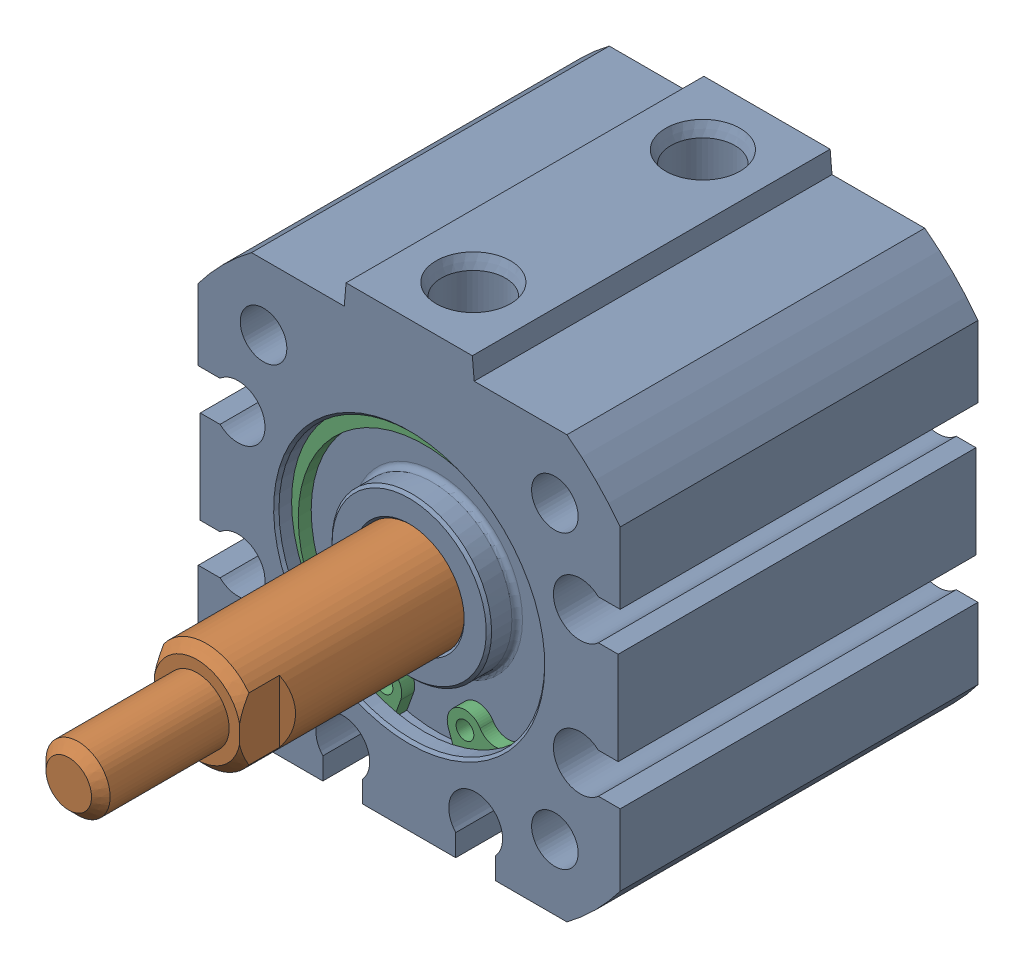
SolidWorks assembly 217-2778-001 Rev2_NCQ8A075-050M_1, configuration Default. Lengths in mm.
Overall size (31.75 33.34 52.54).
3 component instances, 3 part files, 0 mates.
Components (placement in the parent):
- 217-2778-NCQ8A075-050M_NCQ8 Tube_075A_1-1: 217-2778-NCQ8A075-050M_NCQ8 Tube_075A_1 [Default] at origin size (31.75 33.34 26.92)
- 217-2778-NCQ8A075-050M_NCQ8 Rod_075M_1-1: 217-2778-NCQ8A075-050M_NCQ8 Rod_075M_1 [Default] at (0 0 3.8126) x (-1 0 0) z (0 0 1) size (18.95 18.95 35.27)
- 217-2778-NCQ8A075-050M_Snap Ring_075_1-1: 217-2778-NCQ8A075-050M_Snap Ring_075_1 [Default] at (0 0 10.362) size (21 20.74 0.97)
